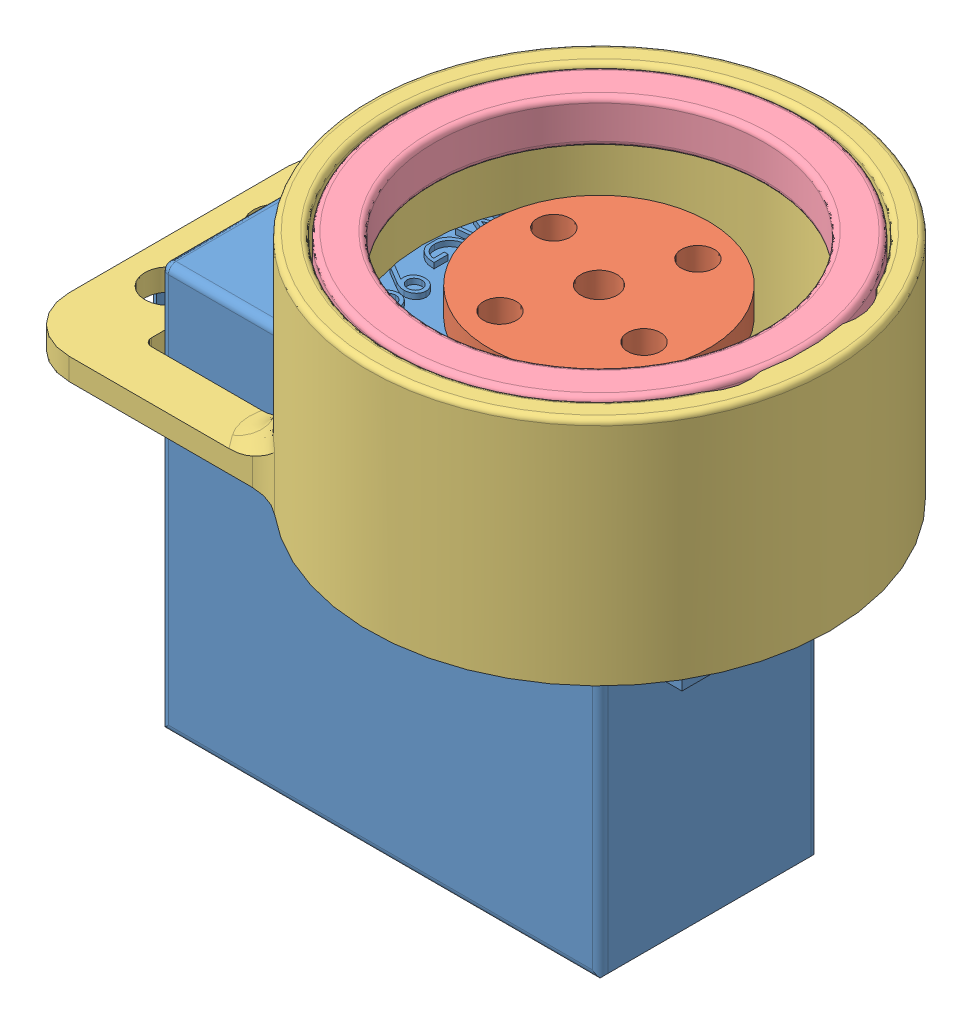
SolidWorks assembly 舵机, configuration 默认. Lengths in mm.
Overall size (62.58 50.13 48.56).
4 component instances, 4 part files, 7 mates.
Components (placement in the parent):
- MG996R-1: MG996R [默认] at (-24.3261 -24.1182 63.95) size (54 43.2 19.9)
- 舵盘-1: 舵盘 [默认] at (5.6739 19.0818 54.0566) x (0.349986 0 -0.936755) z (0 -1 0) size (20 20 4.5)
- 舵机固定件_轴承-1: 舵机固定件_轴承 [默认] at (16.6739 6.7818 64.5) x (-1 0 0) z (0 -1 0) size (59.3 42 21.23)
- 6706一30x37x4轴承-1: 6706一30x37x4轴承 [默认] at (5.6739 25.7818 54) x (-0.392612 0 0.919704) z (0 -1 0) size (37 37 4)
Mates (geometry in assembly coordinates):
- 重合1: coincident anti-aligned: plane of MG996R-1 through (5.6739 19.0818 54.0566) normal (0 1 0); plane of 舵盘-1 through (5.6739 19.0818 54.0566) normal (0 -1 0)
- 同心1: concentric aligned: circle of MG996R-1; circle of 舵盘-1
- 同心7: concentric aligned: cylinder of MG996R-1 through (19.9739 4.7818 49.05) axis (0 -1 0) radius 2.25; circle of 舵机固定件_轴承-1
- 同心8: concentric aligned: circle of MG996R-1; circle of 舵机固定件_轴承-1
- 重合5: coincident anti-aligned: plane of MG996R-1 through (-24.3261 4.7818 63.95) normal (0 1 0); plane of 舵机固定件_轴承-1 through (16.6739 4.7818 64.5) normal (0 -1 0)
- 重合6: coincident anti-aligned: plane of 舵机固定件_轴承-1 through (16.6739 21.7818 64.5) normal (0 1 0); plane of 6706一30x37x4轴承-1 through (5.6739 21.7818 54) normal (0 -1 0)
- 同心9: concentric aligned: circle of 舵机固定件_轴承-1; circle of 6706一30x37x4轴承-1
